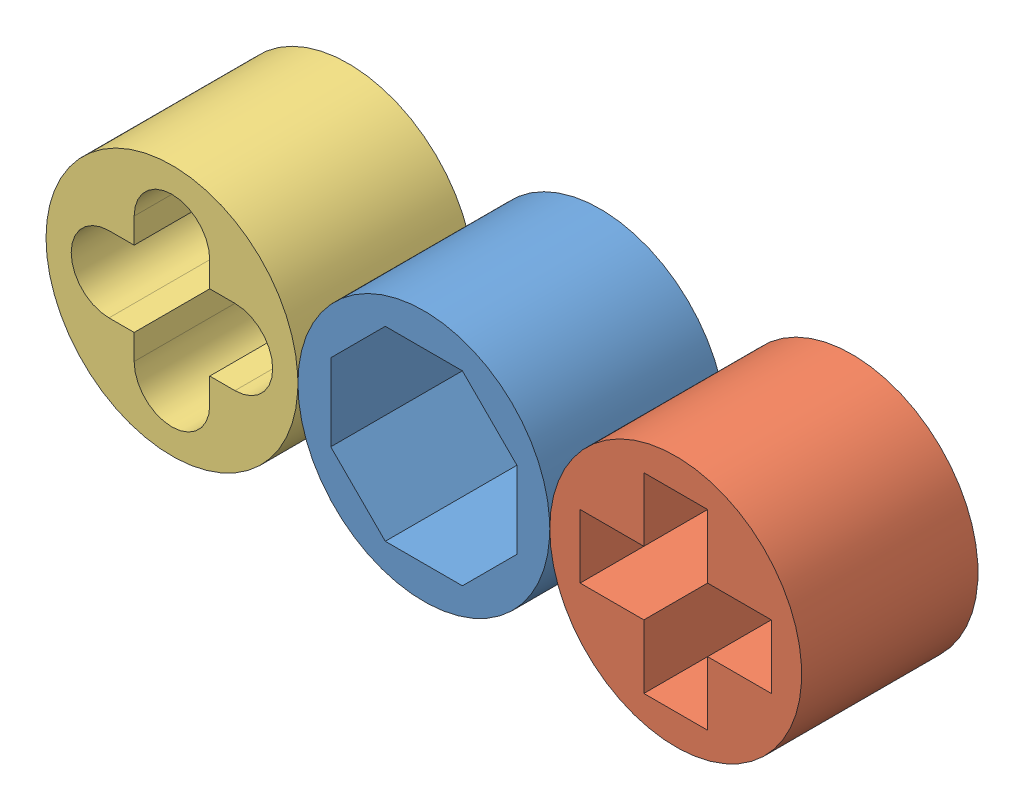
SolidWorks assembly HoleSet, configuration Default. Lengths in mm.
Overall size (30 10 7).
3 component instances, 3 part files, 0 mates.
Components (placement in the parent):
- OctoHole-1: OctoHole [Default] at origin size (10 10 7)
- plusHole-1: plusHole [Default] at (10 0 0) size (10 10 7)
- plusHoleRounded-1: plusHoleRounded [Default] at (-10 0 0) size (10 10 7)
